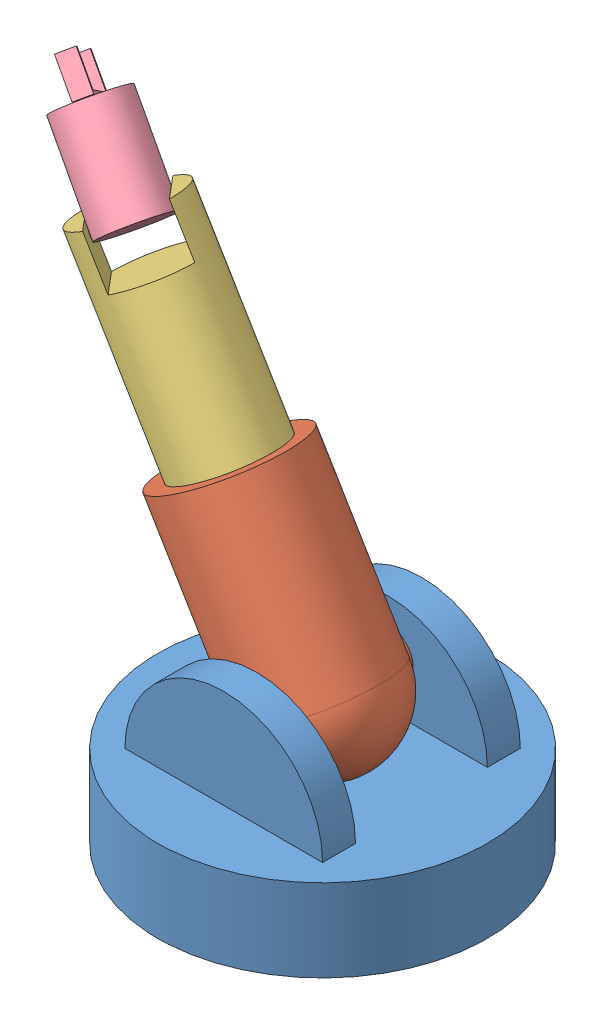
SolidWorks assembly Assem1, configuration Default. Lengths in mm.
Overall size (291.6 350.33 200).
4 component instances, 4 part files, 3 mates.
Components (placement in the parent):
- part1-1: part1 [Default] at (8.3469 47.8681 189.5278) size (200 110 200)
- Part2-1: Part2 [Default] at (8.3469 127.8681 189.5278) x (0.857716 0.514124 0) z (-0.514124 0.857716 0) size (80 100 150)
- Part3-1: Part3 [Default] at (-109.9015 325.1427 189.5278) x (0.581453 0.348529 -0.735146) z (0.514124 -0.857716 0) size (60 60 220)
- Part4-1: Part4 [Default] at (-103.921 316.5095 190.1651) x (0.472491 0.590937 0.65387) z (-0.662318 0.727545 -0.178925) size (50 50 80)
Mates (geometry in assembly coordinates):
- Coincident4: coincident anti-aligned: circle of part1-1; circle of Part2-1
- Coincident6: coincident anti-aligned: circle of Part2-1; circle of Part3-1
- Coincident8: coincident anti-aligned: circle of Part3-1; circle of Part4-1
